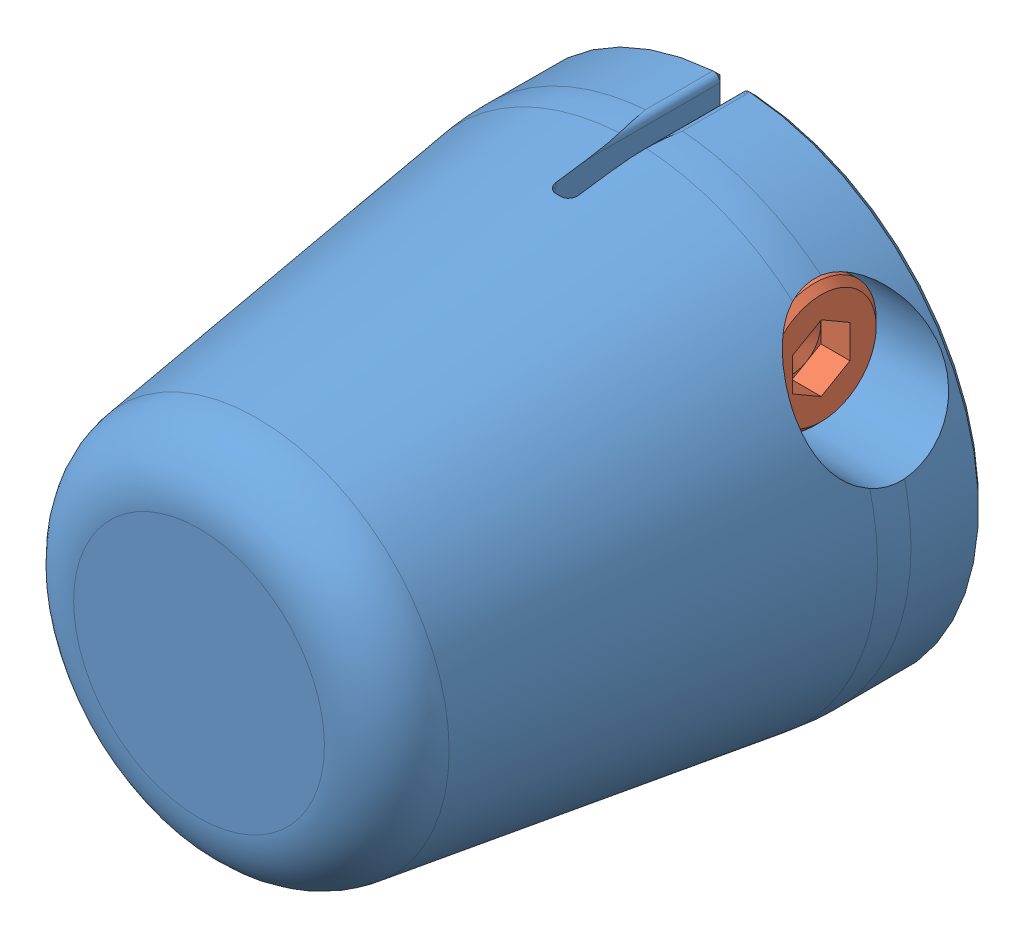
SolidWorks assembly Knob, configuration Default. Lengths in mm.
Overall size (22 21.97 24).
3 component instances, 3 part files, 5 mates.
Components (placement in the parent):
- Knob-1: Knob [Default] at origin size (22 21.97 24)
- socket head cap screw_am-1: socket head cap screw_am [B18.3.1M - 3 x 0.5 x 12 Hex SHCS -- 12NHX] at (7.2 5.5 3.5) x (-1 0 0) z (0 0 1) size (15 5.5 5.5)
- square nut thin grade b_din-1: square nut thin grade b_din [Square nut DIN 562 M3 -N] at (-4.7 5.5 3.5) x (0 0 1) z (-1 0 0) size (5.5 5.5 1.8)
Mates (geometry in assembly coordinates):
- Concentric1: concentric aligned: cylinder of Knob-1 through (15.27 5.5 3.5) axis (1 0 0) radius 1.7; cylinder of socket head cap screw_am-1 through (38.95 5.5 3.5) axis (1 0 0) radius 1.5
- Coincident1: coincident anti-aligned: plane of Knob-1 through (4.2 2.5 3.5) normal (1 0 0); plane of socket head cap screw_am-1 through (4.2 2.75 3.5) normal (-1 0 0)
- Concentric2: concentric anti-aligned: cylinder of socket head cap screw_am-1 through (38.95 5.5 3.5) axis (1 0 0) radius 1.5; cylinder of square nut thin grade b_din-1 through (-2.9 5.5 3.5) axis (-1 0 0) radius 1.25
- Coincident2: coincident anti-aligned: plane of Knob-1 through (-2.9 2.6 15.9769) normal (-1 0 0); plane of square nut thin grade b_din-1 through (-2.9 2.75 0.75) normal (1 0 0)
- Parallel1: parallel aligned: plane of Knob-1 through (0 2.1 0) normal (0 0 -1); plane of square nut thin grade b_din-1 through (-2.9 2.75 0.75) normal (0 0 -1)
